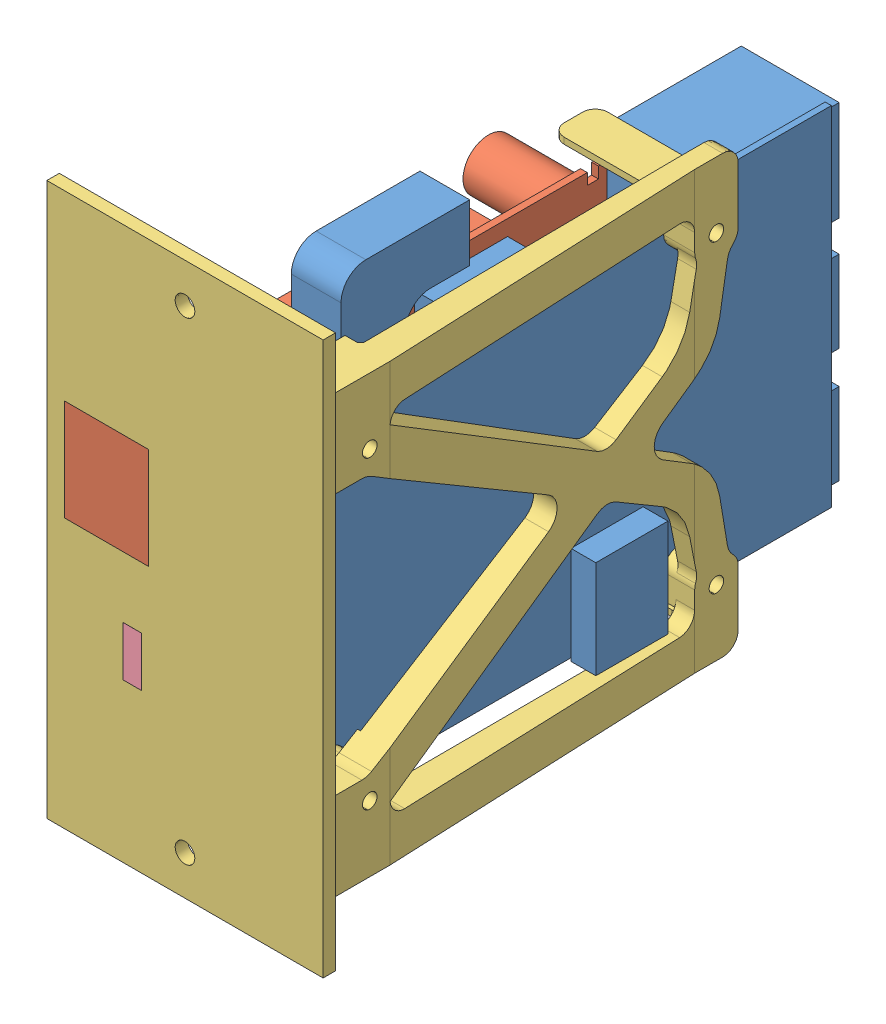
SolidWorks assembly Assem1, configuration Default. Lengths in mm.
Overall size (44.45 88.9 92.25).
5 component instances, 5 part files, 15 mates.
Components (placement in the parent):
- ODroid_C2.2-1: ODroid_C2.2 [Default] at (14 0 -47.5) x (0 0 1) z (-1 0 0) size (87.25 72.47 20.75)
- POE-1: POE [Default] at (-4.75 7 -39.305) x (0 0 -1) z (-1 0 0) size (74.68 25.1 17.85)
- Rack_base-2: Rack_base [Default] x (-1 0 0) z (0 0 -1) size (44.45 88.9 70)
- ODroid-UART-1: ODroid-UART [Default] at (-7 -15 -1) x (0 0 -1) z (0 1 0) size (27.15 6.5 13.57)
- POE-C2-bracket-1: POE-C2-bracket [Default] at (14 0 -47.5) x (0 -1 0) z (0 0 1) size (65.23 19.85 88.12) (hidden)
Mates (geometry in assembly coordinates):
- Coincident12: coincident anti-aligned: plane of Rack_base-2 through (0 0 0) normal (-1 0 0); plane of assembly through (0 0 0) normal (1 0 0)
- Distance7: distance = 0 mm aligned: plane of Rack_base-2; plane of assembly through (0 0 0) normal (0 1 0)
- Coincident3: coincident anti-aligned: plane of Rack_base-2 through (0 0 0) normal (0 0 -1); plane of assembly through (0 0 0) normal (0 0 1)
- Distance1: distance = 5 mm anti-aligned: plane of Rack_base-2 through (0 0 0) normal (0 0 -1); plane of ODroid_C2.2-1 through (17.75 28 -5) normal (0 0 1)
- Distance6: distance = 14 mm aligned: plane of ODroid_C2.2-1 through (14 0 -47.5) normal (-1 0 0); plane of Rack_base-2 through (0 0 0) normal (-1 0 0)
- Coincident13: coincident aligned: plane of ODroid_C2.2-1; plane of Rack_base-2
- Distance3: distance = 18.75 mm aligned: plane of POE-1 through (-4.75 7 -39.305) normal (-1 0 0); plane of ODroid_C2.2-1 through (14 0 -47.5) normal (-1 0 0)
- Coincident17: coincident aligned: plane of POE-1 through (-19.35 -1.15 0) normal (0 0 1); plane of Rack_base-2 through (0 0 0) normal (0 0 1)
- Distance10: distance = 15 mm aligned: plane of ODroid_C2.2-1; plane of ODroid-UART-1 through (-7 -15 -1) normal (0 1 0)
- Distance8: distance = 1 mm anti-aligned: plane of ODroid-UART-1; plane of Rack_base-2 through (0 0 0) normal (0 0 1)
- Distance11: distance = 21 mm aligned: plane of ODroid-UART-1; plane of ODroid_C2.2-1 through (14 0 -47.5) normal (-1 0 0)
- Coincident22: coincident anti-aligned: plane of ODroid_C2.2-1 through (14 0 -47.5) normal (-1 0 0); plane of POE-C2-bracket-1
- Coincident23: coincident aligned: plane of ODroid_C2.2-1 through (14 0 -47.5) normal (0 0 1); plane of POE-C2-bracket-1 through (14 0 -47.5) normal (0 0 1)
- Coincident24: coincident anti-aligned: plane of ODroid_C2.2-1; plane of POE-C2-bracket-1
- Distance12: distance = 7 mm anti-aligned: plane of POE-1; plane of ODroid_C2.2-1
